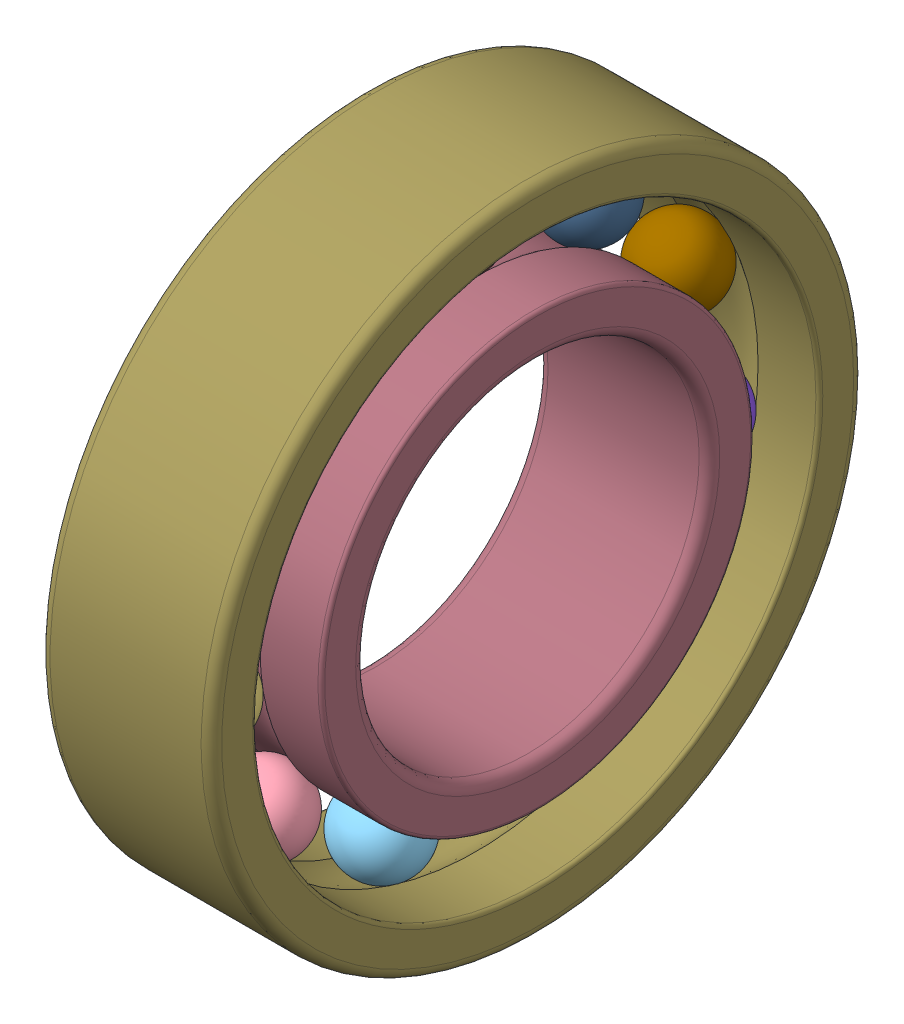
SolidWorks assembly Roulement2AxeMoteur, configuration Défaut. Lengths in mm.
Overall size (5.01 19 19).
14 component instances, 14 part files, 0 mates.
Components (placement in the parent):
- 1_PART_61800_PART1_in_ASM_61800-1: 1_PART_61800_PART1_in_ASM_61800 [Défaut] at (2.5 6.0991 3.9196) size (3.2 3.01 3.02)
- 2_PART_61800_PART2_in_ASM_61800-1: 2_PART_61800_PART2_in_ASM_61800 [Défaut] at (2.5 3.0118 6.5948) size (3.23 3.28 3.31)
- 3_PART_61800_PART3_in_ASM_61800-1: 3_PART_61800_PART3_in_ASM_61800 [Défaut] at (2.5 -1.0318 7.1762) size (3.31 3.03 3.32)
- 4_PART_61800_PART3_in_ASM_61800-1: 4_PART_61800_PART3_in_ASM_61800 [Défaut] at (2.5 -4.7477 5.4792) size (3.18 3.13 3.12)
- 5_PART_61800_PART3_in_ASM_61800-1: 5_PART_61800_PART3_in_ASM_61800 [Défaut] at (2.5 -6.9563 2.0426) size (3.11 3.23 3.11)
- 6_PART_61800_PART3_in_ASM_61800-1: 6_PART_61800_PART3_in_ASM_61800 [Défaut] at (2.5 -6.9563 -2.0426) size (3.2 3.24 3.25)
- 7_PART_61800_PART3_in_ASM_61800-1: 7_PART_61800_PART3_in_ASM_61800 [Défaut] at (2.5 -4.7477 -5.4792) size (3.13 3.32 3.2)
- 8_PART_61800_PART3_in_ASM_61800-1: 8_PART_61800_PART3_in_ASM_61800 [Défaut] at (2.5 -1.0318 -7.1762) size (3.23 3.19 3.29)
- 9_PART_61800_PART3_in_ASM_61800-1: 9_PART_61800_PART3_in_ASM_61800 [Défaut] at (2.5 3.0118 -6.5948) size (3.19 2.92 2.97)
- 10_PART_61800_PART3_in_ASM_61800-1: 10_PART_61800_PART3_in_ASM_61800 [Défaut] at (2.5 6.0991 -3.9196) size (3.35 3.36 3.04)
- 11_PART_61800_PART3_in_ASM_61800-1: 11_PART_61800_PART3_in_ASM_61800 [Défaut] at (2.5 7.25 0) size (3.28 3.11 3.26)
- 12_PART_61800_PART3_in_ASM_61800-1: 12_PART_61800_PART3_in_ASM_61800 [Défaut] at (2.5 0 0) size (5 19 19)
- 13_PART_61800_PART3_in_ASM_61800-1: 13_PART_61800_PART3_in_ASM_61800 [Défaut] at (2.5 0 0) size (5.01 12.6 12.6)
- RoulementAxeMoteur-1: RoulementAxeMoteur [Défaut] at origin
